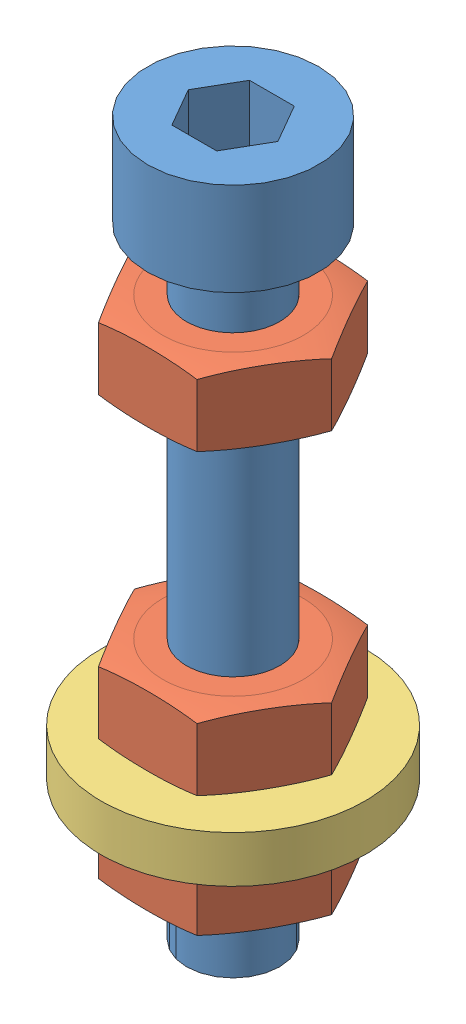
SolidWorks assembly M3_assembly, configuration Valor predeterminado. Lengths in mm.
Overall size (8.5 23 8.5).
5 component instances, 3 part files, 9 mates.
Components (placement in the parent):
- M3_cap_screw-1: M3_cap_screw [Valor predeterminado] at origin size (5.5 23 5.5)
- M3_nut-1: M3_nut [Valor predeterminado] at (0 -7.4 0) size (6.35 3.17 5.5)
- M3_nut-2: M3_nut [Valor predeterminado] at (0 -20.9 0) size (6.35 3.17 5.5)
- M3_nut-3: M3_nut [Valor predeterminado] at (0 -17 0) size (6.35 3.17 5.5)
- arruela_m3-1: arruela_m3 [Valor predeterminado] at (0 -18.5 0) size (8.5 1.5 8.5)
Mates (geometry in assembly coordinates):
- Concêntrico1: concentric anti-aligned: cylinder of M3_cap_screw-1 through (0 -23 0) axis (0 1 0) radius 1.5; cylinder of M3_nut-1 through (0 -5 0) axis (0 -1 0) radius 1.5
- Concêntrico2: concentric anti-aligned: cylinder of M3_cap_screw-1 through (0 -23 0) axis (0 1 0) radius 1.5; cylinder of M3_nut-3 through (0 -12.6 0) axis (0 -1 0) radius 1.5
- Concêntrico3: concentric anti-aligned: cylinder of M3_cap_screw-1 through (0 -23 0) axis (0 1 0) radius 1.5; cylinder of M3_nut-2 through (0 -16.5 0) axis (0 -1 0) radius 1.5
- Distância4: distance = 2 mm anti-aligned: plane of M3_cap_screw-1 through (0 -3 0) normal (0 -1 0); plane of M3_nut-1 through (0 -5 0) normal (0 1 0)
- Distância2: distance = 1.5 mm anti-aligned: plane of M3_nut-3 through (0 -17 0) normal (0 -1 0); plane of M3_nut-2 through (0 -18.5 0) normal (0 1 0)
- Concêntrico4: concentric anti-aligned: cylinder of M3_cap_screw-1 through (0 -23 0) axis (0 1 0) radius 1.5; cylinder of arruela_m3-1 through (0 -15 0) axis (0 -1 0) radius 1.75
- Coincidente1: coincident aligned: plane of arruela_m3-1 through (0 -16.5 0) normal (0 0 1)
- Coincidente3: coincident anti-aligned: plane of M3_nut-2 through (0 -16.5 0) normal (0 1 0); plane of arruela_m3-1 through (0 -16.5 0) normal (0 -1 0)
- Distância3: distance = 9.6 mm anti-aligned: plane of arruela_m3-1 through (0 -17 0) normal (0 1 0); plane of M3_nut-1 through (0 -7.4 0) normal (0 -1 0)
